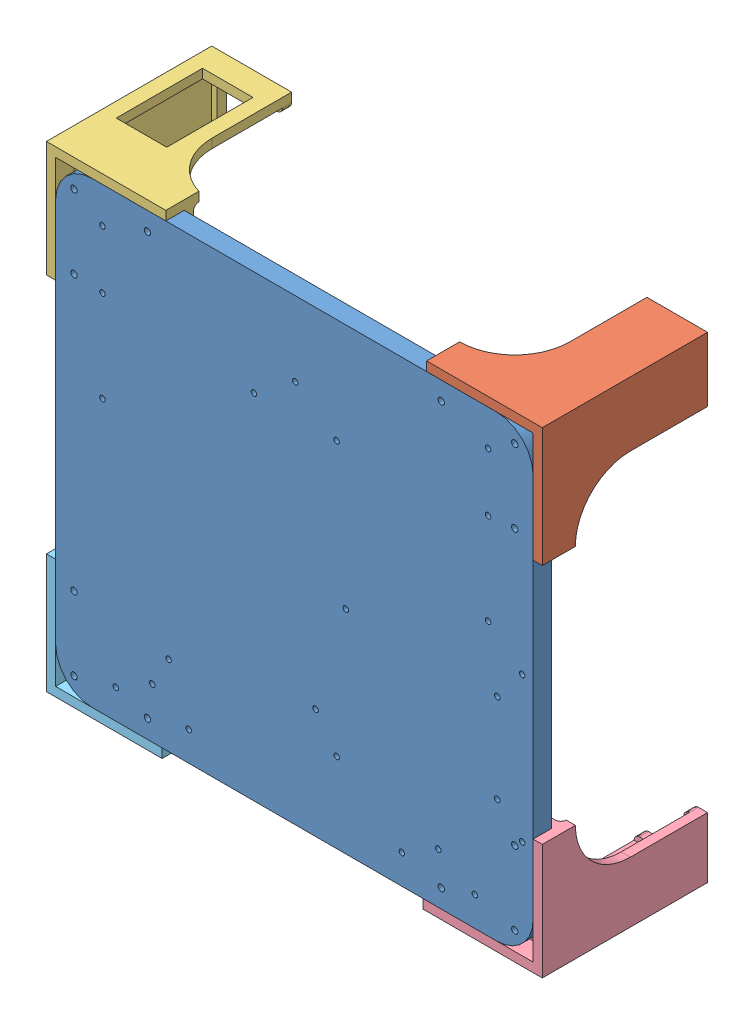
SolidWorks assembly ensBasePatas, configuration Predeterminado. Lengths in mm.
Overall size (270 259.5 90).
5 component instances, 5 part files, 12 mates.
Components (placement in the parent):
- Cyclone_Base_8mm-1: Cyclone_Base_8mm [Predeterminado] at (-151.4267 -133.9581 260) size (260 249.5 10)
- voet_cyclone.v2.trasDer-1: voet_cyclone.v2.trasDer [Predeterminado] at (133.5733 125.0419 270) x (1 0 0) z (0 -1 0) size (63 90 65)
- voet_cyclone.v2.trasIzq-1: voet_cyclone.v2.trasIzq [Predeterminado] at (-136.4267 125.0419 270) x (0 1 0) z (1 0 0) size (63 90 65)
- voet_cyclone.v2.delDer-1: voet_cyclone.v2.delDer [Predeterminado] at (133.5733 -134.4581 270) x (0 -1 0) z (-1 0 0) size (63 90 65)
- voet_cyclone.v2.delIzq-1: voet_cyclone.v2.delIzq [Predeterminado] at (-136.4267 -134.4581 270) x (-1 0 0) z (0 1 0) size (63 90 65)
Mates (geometry in assembly coordinates):
- Coincidente4: coincident aligned: circle of Cyclone_Base_8mm-1; plane of voet_cyclone.v2.trasDer-1 through (128.5733 1.8267 260) normal (0 0 1)
- Coincidente5: coincident anti-aligned: line of Cyclone_Base_8mm-1 through (-111.4267 120.0419 260) axis (1 0 0); line of voet_cyclone.v2.trasDer-1 through (128.5733 120.0419 260) axis (-1 0 0)
- Coincidente6: coincident anti-aligned: line of Cyclone_Base_8mm-1 through (128.5733 100.0419 260) axis (0 -1 0); line of voet_cyclone.v2.trasDer-1 through (128.5733 60.0419 260) axis (0 1 0)
- Coincidente7: coincident aligned: circle of Cyclone_Base_8mm-1; plane of voet_cyclone.v2.trasIzq-1 through (-13.2116 120.0419 260) normal (0 0 1)
- Coincidente8: coincident anti-aligned: line of Cyclone_Base_8mm-1 through (-111.4267 120.0419 260) axis (1 0 0); line of voet_cyclone.v2.trasIzq-1 through (-71.4267 120.0419 260) axis (-1 0 0)
- Coincidente9: coincident anti-aligned: line of Cyclone_Base_8mm-1 through (-131.4267 -109.4581 260) axis (0 1 0); line of voet_cyclone.v2.trasIzq-1 through (-131.4267 120.0419 260) axis (0 -1 0)
- Coincidente10: coincident aligned: circle of Cyclone_Base_8mm-1; plane of voet_cyclone.v2.delDer-1 through (10.3582 -129.4581 260) normal (0 0 1)
- Coincidente11: coincident anti-aligned: line of Cyclone_Base_8mm-1 through (128.5733 100.0419 260) axis (0 -1 0); line of voet_cyclone.v2.delDer-1 through (128.5733 -129.4581 260) axis (0 1 0)
- Coincidente12: coincident anti-aligned: line of Cyclone_Base_8mm-1 through (108.5676 -129.4581 260) axis (-1 0 0); line of voet_cyclone.v2.delDer-1 through (68.5733 -129.4581 260) axis (1 0 0)
- Coincidente13: coincident aligned: circle of Cyclone_Base_8mm-1; plane of voet_cyclone.v2.delIzq-1 through (-131.4267 -11.243 260) normal (0 0 1)
- Coincidente14: coincident anti-aligned: line of Cyclone_Base_8mm-1 through (-131.4267 -109.4581 260) axis (0 1 0); line of voet_cyclone.v2.delIzq-1 through (-131.4267 -69.4581 260) axis (0 -1 0)
- Coincidente15: coincident anti-aligned: line of Cyclone_Base_8mm-1 through (108.5676 -129.4581 260) axis (-1 0 0); line of voet_cyclone.v2.delIzq-1 through (-131.4267 -129.4581 260) axis (1 0 0)
